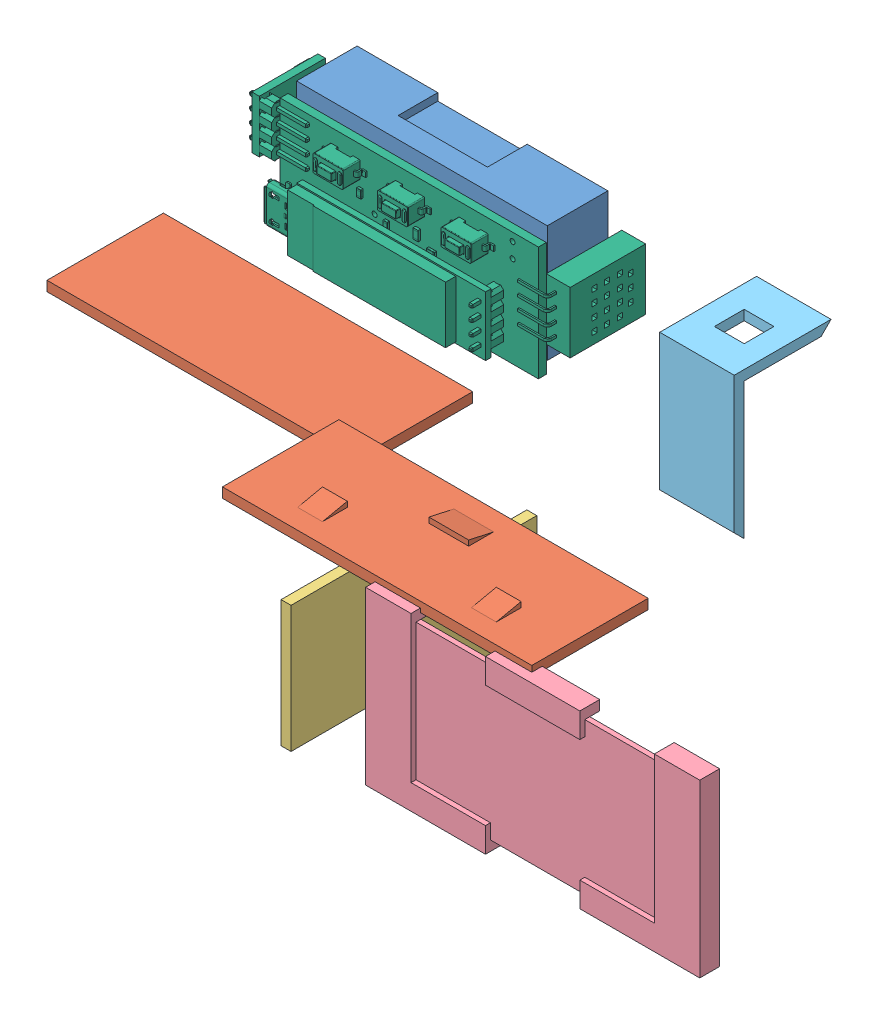
SolidWorks assembly assembly, configuration 00. Lengths in mm.
Overall size (186.56 60.26 78.54).
14 component instances, 12 part files, 3 mates.
Components (placement in the parent):
- OLED 0.96inches.step-1: OLED 0.96inches.step [00] at (52.0262 -9.6409 29.2641) x (-1 0 0) z (0 0 1) size (38 12 11.5) (hidden)
- 18650-1: 18650 [00] at (5.7017 17.3843 -22.8804) x (0 0 -1) z (1 0 0) size (18 18 65) (hidden)
- 14500-1: 14500 [00] at (9.1293 2.6157 -0.9544) x (0 0 -1) z (1 0 0) size (14.05 14.05 48.7) (hidden)
- BMP180-2: BMP180 [00] at (21.5262 -7.828 20.853) x (0 0 1) z (-1 0 0) size (13.3 10.6 11.6) (hidden)
- AM2320 with case-1: AM2320 with case [Default] at (21.5262 -19.7999 20.0141) x (0 1 0) z (0 0 1) size (12.3 4.8 23.2) (hidden)
- AAAbatteryCase-1: AAAbatteryCase [00] at (47.7762 -14.3909 24.6141) x (1 0 0) z (0 1 0) size (52 12.2 23.5)
- weather station SCH-1: weather station SCH [00] at (21.0262 -25.6409 26.0255) size (137.15 49.77 15.11) (hidden)
- Деталь2-1: Деталь2 [00] at (-1520.1512 -53.2815 33.5841) x (0 0 1) z (0 -1 0) size (23.45 62.3 3.07)
- Деталь3-1: Деталь3 [00] at (102.4359 -205.5547 -26.8697) x (0 1 0) z (-1 0 0) size (25.5 23.45 2)
- Деталь2-2: Деталь2 [00] at (-1431.6333 -20.467 63.87) x (0 0 -1) z (0 1 0) size (23.45 62.3 3.07)
- Деталь3-2: Деталь3 [00] at (82.1589 125.424 -19.0991) x (0 -1 0) z (1 0 0) size (25.5 23.45 2)
- крышка-1: крышка [Default] at (134.4145 -36.9032 84.9509) x (1 0 0) z (0 -1 0) size (67.3 4 34.5)
- зацеп малый-1: зацеп малый [Default] at (123.4198 0.8591 35.3641) x (0 0 -1) z (0 1 0) size (19.5 15 29.5)
- PCB STEP.step-1: PCB STEP.step [По умолчанию] at (49.8203 -14.1633 29.2055) x (-1 0 0) z (0 0 1) size (62.5 23 22.4)
Mates (geometry in assembly coordinates):
- Расстояние1: distance = 3 mm anti-aligned: plane of PCB STEP.step-1 through (75.8203 -2.6633 27.6141) normal (0 0 -1); plane of AAAbatteryCase-1 through (47.7762 -14.3909 24.6141) normal (0 0 1)
- Параллельность1: parallel aligned: plane of AAAbatteryCase-1 through (22.5262 -2.6409 12.4141) normal (-1 0 0); plane of PCB STEP.step-1 through (23.8203 -25.6633 27.6141) normal (-1 0 0)
- Расстояние2: distance = 0.0224 mm aligned: plane of AAAbatteryCase-1 through (22.5262 -2.6409 12.4141) normal (0 1 0); plane of PCB STEP.step-1 through (23.8203 -2.6633 27.6141) normal (0 1 0)
